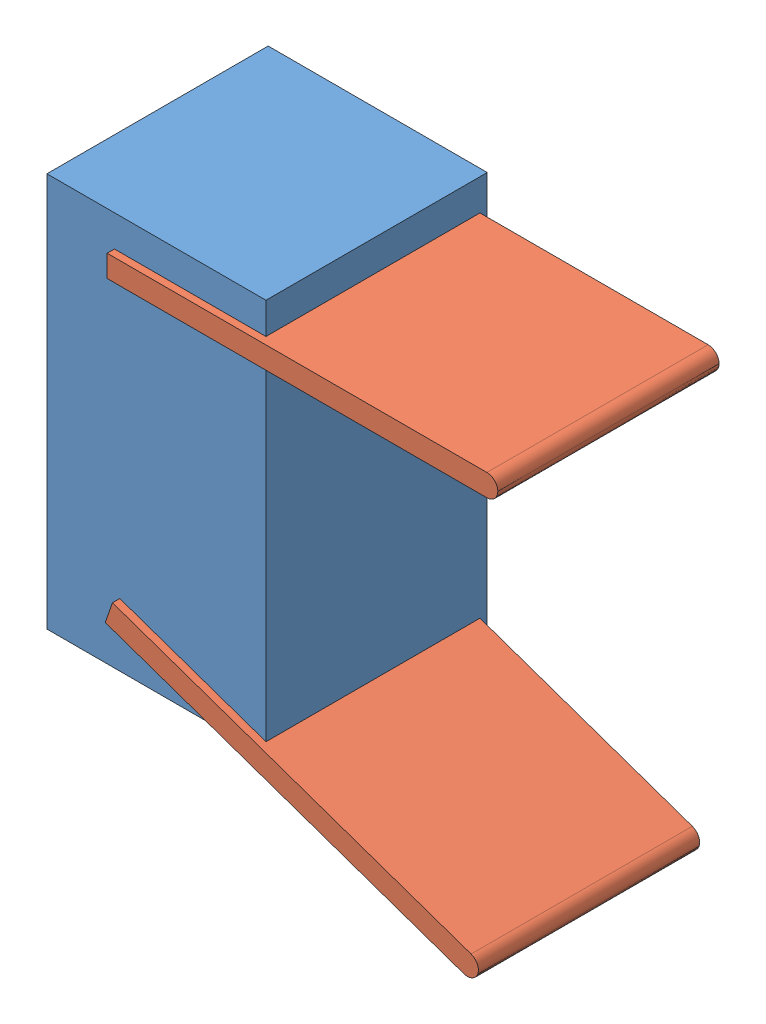
SolidWorks assembly simulation_assembly, configuration Default. Lengths in mm.
Overall size (66.16 78.58 100).
3 component instances, 2 part files, 4 mates.
Components (placement in the parent):
- simulation_body-1: simulation_body [Default] at origin size (30 54 30.3)
- simulation_arm-3: simulation_arm [Default] at (-1.5 21.2 1) size (53.5 3 30.3)
- simulation_arm-4: simulation_arm [Default] at (-1.5 -21.2 1) x (0.944354 -0.328932 0) z (0 0 1) size (53.5 3 30.3)
Mates (geometry in assembly coordinates):
- Distance2: distance = 1 mm: plane of simulation_arm-3 through (-1.5 21.2 31.3) normal (0 0 1); plane of simulation_body-1 through (0 0 30.3) normal (0 0 1)
- Coincident11: coincident: line of simulation_body-1 through (-1.5 21.2 0) axis (0 0 1); line of simulation_arm-3 through (-1.5 21.2 -6.6722) axis (0 0 1)
- Coincident13: coincident: line of simulation_body-1 through (-1.5 -21.2 0) axis (0 0 1); line of simulation_arm-4 through (-1.5 -21.2 -6.6722) axis (0 0 1)
- Distance4: distance = 1 mm: plane of simulation_arm-4 through (-1.5 -21.2 31.3) normal (0 0 1); plane of simulation_body-1 through (0 0 30.3) normal (0 0 1)
